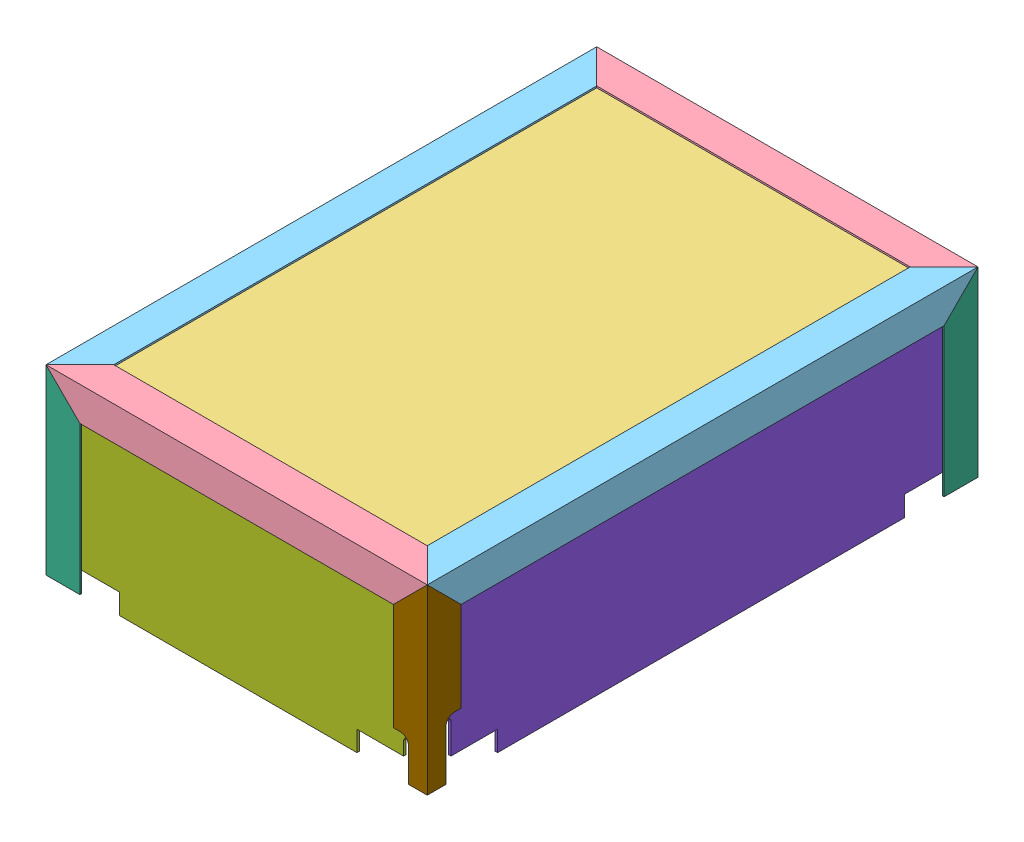
SolidWorks assembly couvercle, configuration Défaut. Lengths in mm.
Overall size (450 215 650).
13 component instances, 9 part files, 31 mates.
Components (placement in the parent):
- plaque_acrylique_680x210-2: plaque_acrylique_680x210 [Défaut] at (-583.1966 1.1201 -270.8343) x (0 0 -1) z (1 0 0) size (640 210 3)
- plaque_acrylique_380x210-2: plaque_acrylique_380x210 [Défaut] at (-330.1966 1.1201 -613.8343) size (440 210 3)
- plaque_acrylique_380x680-1: plaque_acrylique_380x680 [Défaut] at (-330.1966 106.1201 -270.8343) x (1 0 0) z (0 1 0) size (440 640 3)
- eclisse_40x40x404_bisote_x2-1: eclisse_40x40x404_bisote_x2 [Défaut] at (-135.1966 91.0065 -595.8343) x (0 0 1) z (0 -1 0) size (40 450 40)
- eclisse_40x40x704_bisote_x2-1: eclisse_40x40x704_bisote_x2 [Défaut] at (-155.3102 91.1201 -615.8343) x (0 -1 0) z (-1 0 0) size (40 650 40)
- eclisse_40x40x404_bisote_x2-2: eclisse_40x40x404_bisote_x2 [Défaut] at (-585.1966 91.0065 14.1657) x (0 0 -1) z (0 -1 0) size (40 450 40)
- eclisse_40x40x704_bisote_x2-2: eclisse_40x40x704_bisote_x2 [Défaut] at (-565.1966 91.0065 -615.8343) x (1 0 0) z (0 -1 0) size (40 650 40)
- eclisse_40x40x222_bisote_x1-1: eclisse_40x40x222_bisote_x1 [Défaut] at (-565.083 111.1201 -595.8343) x (0 0 1) z (1 0 0) size (40 215 40)
- eclisse_40x40x222_bisote_x1-2: eclisse_40x40x222_bisote_x1 [Défaut] at (-155.1966 111.1201 -595.7207) x (-1 0 0) z (0 0 1) size (40 215 40)
- eclisse_40x40x222_bisote_x1-4: eclisse_40x40x222_bisote_x1 [Défaut] at (-565.1966 111.1201 14.052) x (1 0 0) z (0 0 -1) size (40 215 40)
- plaque_acrylique_380x210_Moteur-1: plaque_acrylique_380x210_Moteur [Défaut] at (-330.1966 1.1201 29.1657) size (440 210 3)
- plaque_acrylique_680x210_moteur-1: plaque_acrylique_680x210_moteur [Défaut] at (-140.1966 1.1201 -270.8343) x (0 0 -1) z (1 0 0) size (640 210 3)
- eclisse_40x40x222_bisote_x1_Moteur-1: eclisse_40x40x222_bisote_x1_Moteur [Défaut] at (-155.3102 111.1201 14.1657) x (0 0 -1) z (-1 0 0) size (40 215 40)
Mates (geometry in assembly coordinates):
- Coïncidente1: coincident anti-aligned: plane of plaque_acrylique_380x680-1 through (-330.1966 109.1201 -270.8343) normal (0 1 0); plane of eclisse_40x40x704_bisote_x2-1 through (-137.1966 109.1201 34.1657) normal (0 -1 0)
- Coïncidente2: coincident anti-aligned: plane of eclisse_40x40x704_bisote_x2-1 through (-137.1966 109.1201 34.1657) normal (-1 0 0); plane of plaque_acrylique_680x210_moteur-1 through (-137.1966 1.1201 -270.8343) normal (1 0 0)
- Coïncidente3: coincident anti-aligned: plane of plaque_acrylique_380x210-2 through (-330.1966 1.1201 -613.8343) normal (0 0 -1); plane of eclisse_40x40x404_bisote_x2-1 through (-585.1966 109.1201 -613.8343) normal (0 0 1)
- Coïncidente4: coincident anti-aligned: plane of plaque_acrylique_380x680-1 through (-330.1966 109.1201 -270.8343) normal (0 1 0); plane of eclisse_40x40x404_bisote_x2-1 through (-585.1966 109.1201 -613.8343) normal (0 -1 0)
- Coïncidente5: coincident anti-aligned: plane of plaque_acrylique_680x210-2 through (-583.1966 1.1201 -270.8343) normal (-1 0 0); plane of eclisse_40x40x704_bisote_x2-2 through (-583.1966 109.1201 34.1657) normal (1 0 0)
- Coïncidente6: coincident anti-aligned: plane of plaque_acrylique_380x680-1 through (-330.1966 109.1201 -270.8343) normal (0 1 0); plane of eclisse_40x40x704_bisote_x2-2 through (-583.1966 109.1201 34.1657) normal (0 -1 0)
- Coïncidente7: coincident anti-aligned: plane of eclisse_40x40x404_bisote_x2-2 through (-135.1966 109.1201 32.1657) normal (0 0 -1); plane of plaque_acrylique_380x210_Moteur-1 through (-330.1966 1.1201 32.1657) normal (0 0 1)
- Coïncidente9: coincident anti-aligned: plane of plaque_acrylique_380x210_Moteur-1 through (-330.1966 1.1201 32.1657) normal (0 0 1); plane of eclisse_40x40x222_bisote_x1_Moteur-1 through (-137.1966 -103.8799 32.1657) normal (0 0 -1)
- Coïncidente10: coincident anti-aligned: plane of plaque_acrylique_680x210_moteur-1 through (-137.1966 1.1201 -270.8343) normal (1 0 0); plane of eclisse_40x40x222_bisote_x1_Moteur-1 through (-137.1966 -103.8799 32.1657) normal (-1 0 0)
- Coïncidente11: coincident anti-aligned: plane of plaque_acrylique_380x210-2 through (-330.1966 1.1201 -613.8343) normal (0 0 -1); plane of eclisse_40x40x222_bisote_x1-2 through (-137.1966 -103.8799 -613.8343) normal (0 0 1)
- Coïncidente12: coincident anti-aligned: plane of eclisse_40x40x222_bisote_x1-2 through (-137.1966 -103.8799 -613.8343) normal (-1 0 0); plane of plaque_acrylique_680x210_moteur-1 through (-137.1966 1.1201 -270.8343) normal (1 0 0)
- Coïncidente13: coincident anti-aligned: plane of plaque_acrylique_680x210-2 through (-583.1966 1.1201 -270.8343) normal (-1 0 0); plane of eclisse_40x40x222_bisote_x1-1 through (-583.1966 -103.8799 -613.8343) normal (1 0 0)
- Coïncidente14: coincident anti-aligned: plane of plaque_acrylique_380x210-2 through (-330.1966 1.1201 -613.8343) normal (0 0 -1); plane of eclisse_40x40x222_bisote_x1-1 through (-583.1966 -103.8799 -613.8343) normal (0 0 1)
- Coïncidente15: coincident anti-aligned: plane of eclisse_40x40x222_bisote_x1-4 through (-583.1966 -103.8799 32.1657) normal (0 0 -1); plane of plaque_acrylique_380x210_Moteur-1 through (-330.1966 1.1201 32.1657) normal (0 0 1)
- Coïncidente16: coincident anti-aligned: plane of plaque_acrylique_680x210-2 through (-583.1966 1.1201 -270.8343) normal (-1 0 0); plane of eclisse_40x40x222_bisote_x1-4 through (-583.1966 -103.8799 32.1657) normal (1 0 0)
- Coïncidente19: coincident anti-aligned: line of plaque_acrylique_380x210_Moteur-1 through (-140.1966 -26.8799 29.1657) axis (0 1 0); line of plaque_acrylique_680x210_moteur-1 through (-140.1966 106.1201 29.1657) axis (0 -1 0)
- Coïncidente21: coincident aligned: line of plaque_acrylique_680x210-2 through (-580.1966 106.1201 29.1657) axis (0 -1 0); line of plaque_acrylique_380x210_Moteur-1 through (-580.1966 106.1201 29.1657) axis (0 -1 0)
- Coïncidente23: coincident anti-aligned: line of plaque_acrylique_680x210-2 through (-580.1966 -26.8799 -610.8343) axis (0 1 0); line of plaque_acrylique_380x210-2 through (-580.1966 106.1201 -610.8343) axis (0 -1 0)
- Coïncidente28: coincident anti-aligned: line of plaque_acrylique_380x680-1 through (-580.1966 106.1201 29.1657) axis (1 0 0); line of plaque_acrylique_380x210_Moteur-1 through (-140.1966 106.1201 29.1657) axis (-1 0 0)
- Coïncidente29: coincident aligned: line of plaque_acrylique_680x210-2 through (-580.1966 106.1201 -610.8343) axis (0 0 1); line of plaque_acrylique_380x680-1 through (-580.1966 106.1201 -610.8343) axis (0 0 1)
- Coïncidente30: coincident anti-aligned: plane of plaque_acrylique_380x680-1 through (-330.1966 109.1201 -270.8343) normal (0 1 0); plane of eclisse_40x40x404_bisote_x2-2 through (-135.1966 109.1201 32.1657) normal (0 -1 0)
- Coïncidente31: coincident anti-aligned: line of eclisse_40x40x404_bisote_x2-2 through (-135.1966 111.1201 34.1657) axis (-0.707107 -0.707107 0); line of eclisse_40x40x222_bisote_x1_Moteur-1 through (-175.1966 71.1201 34.1657) axis (0.707107 0.707107 0)
- Coïncidente32: coincident anti-aligned: line of eclisse_40x40x704_bisote_x2-1 through (-135.1966 71.1201 -5.8343) axis (0 0.707107 0.707107); line of eclisse_40x40x222_bisote_x1_Moteur-1 through (-135.1966 111.1201 34.1657) axis (0 -0.707107 -0.707107)
- Coïncidente35: coincident anti-aligned: line of eclisse_40x40x404_bisote_x2-2 through (-545.1966 71.1201 34.1657) axis (-0.707107 0.707107 0); line of eclisse_40x40x222_bisote_x1-4 through (-585.1966 111.1201 34.1657) axis (0.707107 -0.707107 0)
- Coïncidente36: coincident anti-aligned: line of eclisse_40x40x704_bisote_x2-2 through (-585.1966 111.1201 34.1657) axis (0 -0.707107 -0.707107); line of eclisse_40x40x222_bisote_x1-4 through (-585.1966 71.1201 -5.8343) axis (0 0.707107 0.707107)
- Coïncidente37: coincident anti-aligned: line of eclisse_40x40x404_bisote_x2-2 through (-585.1966 111.1201 34.1657) axis (0.707107 0 -0.707107); line of eclisse_40x40x704_bisote_x2-2 through (-545.1966 111.1201 -5.8343) axis (-0.707107 0 0.707107)
- Coïncidente38: coincident anti-aligned: line of eclisse_40x40x404_bisote_x2-1 through (-545.1966 111.1201 -575.8343) axis (-0.707107 0 -0.707107); line of eclisse_40x40x704_bisote_x2-2 through (-585.1966 111.1201 -615.8343) axis (0.707107 0 0.707107)
- Coïncidente39: coincident anti-aligned: line of eclisse_40x40x704_bisote_x2-2 through (-585.1966 71.1201 -575.8343) axis (0 0.707107 -0.707107); line of eclisse_40x40x222_bisote_x1-1 through (-585.1966 111.1201 -615.8343) axis (0 -0.707107 0.707107)
- Coïncidente40: coincident anti-aligned: line of eclisse_40x40x404_bisote_x2-1 through (-175.1966 71.1201 -615.8343) axis (0.707107 0.707107 0); line of eclisse_40x40x222_bisote_x1-2 through (-135.1966 111.1201 -615.8343) axis (-0.707107 -0.707107 0)
- Coïncidente41: coincident: line of plaque_acrylique_380x210-2 through (-140.1966 106.1201 -610.8343) axis (-1 0 0); plane of plaque_acrylique_380x680-1 through (-330.1966 106.1201 -270.8343) normal (0 -1 0)
- Coïncidente42: coincident: plane of plaque_acrylique_380x680-1 through (-330.1966 106.1201 -270.8343) normal (0 -1 0); line of plaque_acrylique_680x210_moteur-1 through (-140.1966 106.1201 -610.8343) axis (0 0 1)
